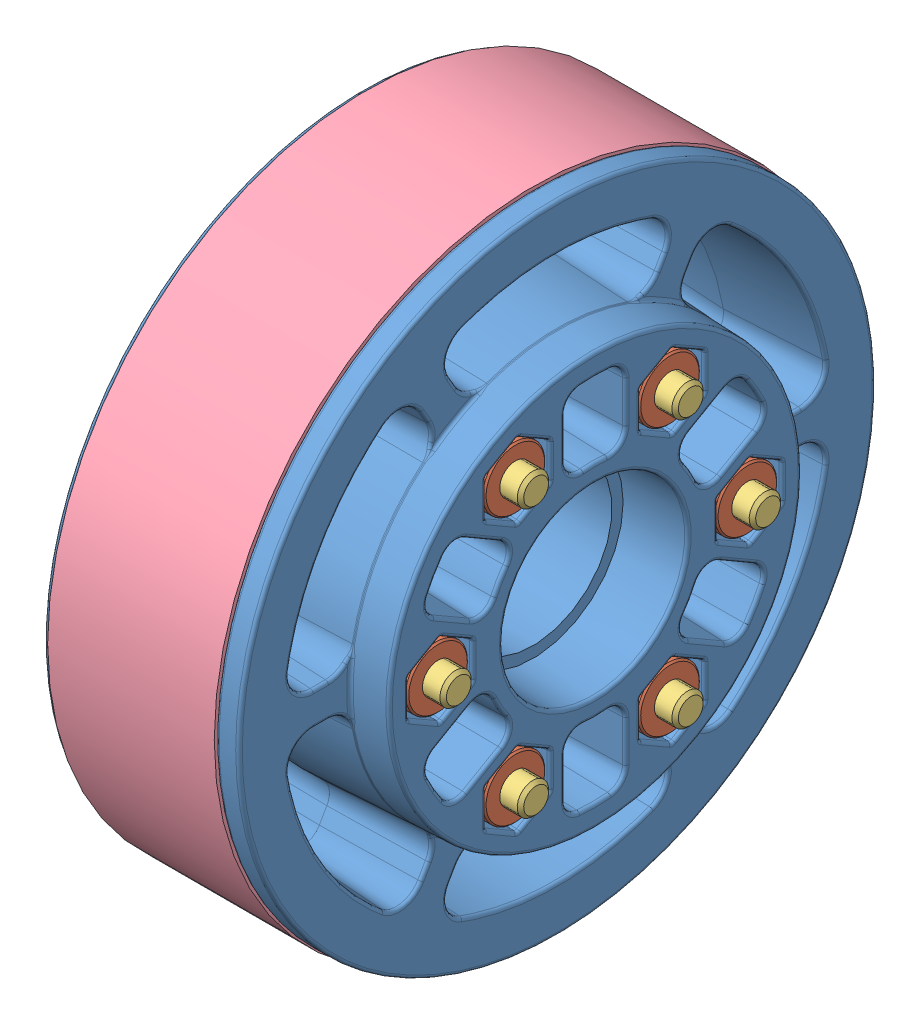
SolidWorks assembly 4in. Plaction Wheel W Blue Nitrile Tread, configuration Default. Lengths in mm.
Overall size (44.45 98.55 98.55).
16 component instances, 4 part files, 2 mates.
Components (placement in the parent):
- 4in Plaction Wheel-1: 4in Plaction Wheel [Default] at (-2.0376 53.0117 94.3912) size (44.45 98.05 98.05)
  - 4MW_d01-1: 4MW_d01 [Default] at origin size (22.87 98.05 98.05)
  - 4MW_d01-2: 4MW_d01 [Default] at (41.656 0 0) x (-1 0 0) z (0 0 -1) size (22.87 98.05 98.05)
  - 10-32_nylock_nut-1: 10-32_nylock_nut [Default] at (130.8703 5.9047 -125.8472) x (0 -0.212137 0.97724) z (-1 0 0) size (11.98 11.69 7.5)
  - 10-32_nylock_nut-2: 10-32_nylock_nut [Default] at (130.8703 106.0345 68.0372) x (0 -0.740246 -0.672336) z (-1 0 0) size (11.98 11.69 7.5)
  - 10-32_nylock_nut-3: 10-32_nylock_nut [Default] at (130.8703 -5.9047 125.8472) x (0 0.212137 -0.97724) z (-1 0 0) size (11.98 11.69 7.5)
  - 10-32_nylock_nut-4: 10-32_nylock_nut [Default] at (130.8703 -111.9392 57.81) x (0 0.952383 -0.304904) z (-1 0 0) size (11.98 11.69 7.5)
  - 10-32_nylock_nut-5: 10-32_nylock_nut [Default] at (130.8703 -106.0345 -68.0372) x (0 0.740246 0.672336) z (-1 0 0) size (11.98 11.69 7.5)
  - 10-32_nylock_nut-6: 10-32_nylock_nut [Default] at (130.8703 111.9392 -57.81) x (0 -0.952383 0.304904) z (-1 0 0) size (11.98 11.69 7.5)
  - 10-32x1500_shcs-1: 10-32x1500_shcs [Default] at (58.0517 58.1538 -90.8088) x (0 -0.164314 0.986408) z (1 0 0) size (7.94 7.94 42.93)
  - 10-32x1500_shcs-2: 10-32x1500_shcs [Default] at (58.0517 49.5658 95.7671) x (0 -0.772098 -0.635504) z (1 0 0) size (7.94 7.94 42.93)
  - 10-32x1500_shcs-3: 10-32x1500_shcs [Default] at (58.0517 -58.1538 90.8088) x (0 0.164314 -0.986408) z (1 0 0) size (7.94 7.94 42.93)
  - 10-32x1500_shcs-4: 10-32x1500_shcs [Default] at (58.0517 -107.7197 -4.9583) x (0 0.936411 -0.350904) z (1 0 0) size (7.94 7.94 42.93)
  - 10-32x1500_shcs-5: 10-32x1500_shcs [Default] at (58.0517 -49.5658 -95.7671) x (0 0.772098 0.635504) z (1 0 0) size (7.94 7.94 42.93)
  - 10-32x1500_shcs-6: 10-32x1500_shcs [Default] at (58.0517 107.7197 4.9583) x (0 -0.936411 0.350904) z (1 0 0) size (7.94 7.94 42.93)
- Blue Nitrile Tread Representation-1: Blue Nitrile Tread Representation [Default] at (4.5664 53.0117 94.3912) x (0 0 -1) z (1 0 0) size (98.55 98.55 25.65)
Mates (geometry in assembly coordinates):
- Concentric1: concentric anti-aligned: circle of 4in Plaction Wheel-1/4MW_d01-2; cylinder of Blue Nitrile Tread Representation-1 through (30.2204 53.0117 94.3912) axis (-1 0 0) radius 45.72
- Coincident2: coincident aligned: circle of 4in Plaction Wheel-1/4MW_d01-2; plane of Blue Nitrile Tread Representation-1 through (30.2204 53.0117 94.3912) normal (1 0 0)
